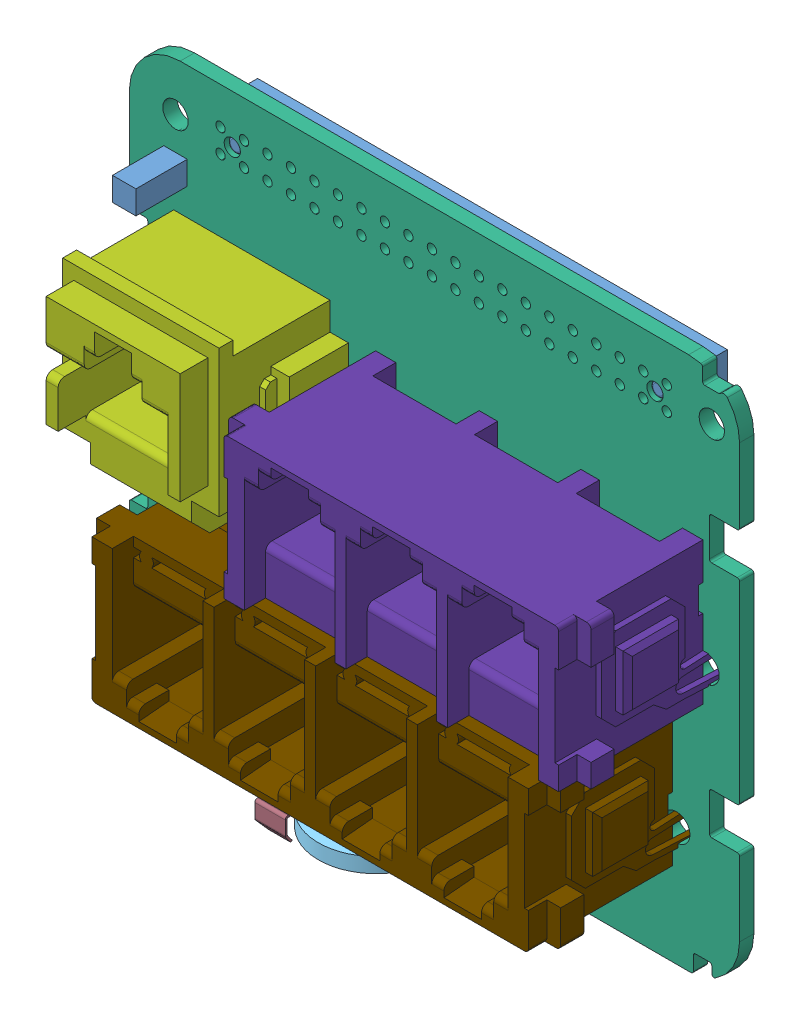
SolidWorks assembly Mainboard_Rpi4, configuration Défaut. Lengths in mm.
Overall size (66 57.75 22.04).
213 component instances, 24 part files, 0 mates.
Components (placement in the parent):
- Mainboard_Rpi4.step-1: Mainboard_Rpi4.step [Défaut] at origin size (66 57.75 22.04)
  - J5.step-1: J5.step [Défaut] at origin size (50.8 7.2 4.95)
    - m20-7812045_asm.step-1: m20-7812045_asm.step [Défaut] at (4.8701 0.0001 -1.7297) x (1 0 0) z (0 1 0) size (50.8 4.95 7.2)
      - M20-78120_MOULD.step-1: M20-78120_MOULD.step [Défaut] at origin size (50.8 4.95 5.08)
      - M20-781_CONTACT.step-1: M20-781_CONTACT.step [Défaut] at (-0.75 1.3 -2.135) size (1.5 2.8 2.83)
      - M20-781_CONTACT.step-2: M20-781_CONTACT.step [Défaut] at (1.79 1.3 -2.135) size (1.5 2.8 2.83)
      - M20-781_CONTACT.step-3: M20-781_CONTACT.step [Défaut] at (4.33 1.3 -2.135) size (1.5 2.8 2.83)
      - M20-781_CONTACT.step-4: M20-781_CONTACT.step [Défaut] at (6.87 1.3 -2.135) size (1.5 2.8 2.83)
      - M20-781_CONTACT.step-5: M20-781_CONTACT.step [Défaut] at (9.41 1.3 -2.135) size (1.5 2.8 2.83)
      - M20-781_CONTACT.step-6: M20-781_CONTACT.step [Défaut] at (11.95 1.3 -2.135) size (1.5 2.8 2.83)
      - M20-781_CONTACT.step-7: M20-781_CONTACT.step [Défaut] at (14.49 1.3 -2.135) size (1.5 2.8 2.83)
      - M20-781_CONTACT.step-8: M20-781_CONTACT.step [Défaut] at (17.03 1.3 -2.135) size (1.5 2.8 2.83)
      - M20-781_CONTACT.step-9: M20-781_CONTACT.step [Défaut] at (19.57 1.3 -2.135) size (1.5 2.8 2.83)
      - M20-781_CONTACT.step-10: M20-781_CONTACT.step [Défaut] at (22.11 1.3 -2.135) size (1.5 2.8 2.83)
      - M20-781_CONTACT.step-11: M20-781_CONTACT.step [Défaut] at (24.65 1.3 -2.135) size (1.5 2.8 2.83)
      - M20-781_CONTACT.step-12: M20-781_CONTACT.step [Défaut] at (27.19 1.3 -2.135) size (1.5 2.8 2.83)
      - M20-781_CONTACT.step-13: M20-781_CONTACT.step [Défaut] at (29.73 1.3 -2.135) size (1.5 2.8 2.83)
      - M20-781_CONTACT.step-14: M20-781_CONTACT.step [Défaut] at (32.27 1.3 -2.135) size (1.5 2.8 2.83)
      - M20-781_CONTACT.step-15: M20-781_CONTACT.step [Défaut] at (34.81 1.3 -2.135) size (1.5 2.8 2.83)
      - M20-781_CONTACT.step-16: M20-781_CONTACT.step [Défaut] at (37.35 1.3 -2.135) size (1.5 2.8 2.83)
      - M20-781_CONTACT.step-17: M20-781_CONTACT.step [Défaut] at (39.89 1.3 -2.135) size (1.5 2.8 2.83)
      - M20-781_CONTACT.step-18: M20-781_CONTACT.step [Défaut] at (42.43 1.3 -2.135) size (1.5 2.8 2.83)
      - M20-781_CONTACT.step-19: M20-781_CONTACT.step [Défaut] at (44.97 1.3 -2.135) size (1.5 2.8 2.83)
      - M20-781_CONTACT.step-20: M20-781_CONTACT.step [Défaut] at (47.51 1.3 -2.135) size (1.5 2.8 2.83)
      - M20-781_CONTACT.step-21: M20-781_CONTACT.step [Défaut] at (0.75 1.3 2.135) x (-1 0 0) z (0 0 -1) size (1.5 2.8 2.83)
      - M20-781_CONTACT.step-22: M20-781_CONTACT.step [Défaut] at (3.29 1.3 2.135) x (-1 0 0) z (0 0 -1) size (1.5 2.8 2.83)
      - M20-781_CONTACT.step-23: M20-781_CONTACT.step [Défaut] at (5.83 1.3 2.135) x (-1 0 0) z (0 0 -1) size (1.5 2.8 2.83)
      - M20-781_CONTACT.step-24: M20-781_CONTACT.step [Défaut] at (8.37 1.3 2.135) x (-1 0 0) z (0 0 -1) size (1.5 2.8 2.83)
      - M20-781_CONTACT.step-25: M20-781_CONTACT.step [Défaut] at (10.91 1.3 2.135) x (-1 0 0) z (0 0 -1) size (1.5 2.8 2.83)
      - M20-781_CONTACT.step-26: M20-781_CONTACT.step [Défaut] at (13.45 1.3 2.135) x (-1 0 0) z (0 0 -1) size (1.5 2.8 2.83)
      - M20-781_CONTACT.step-27: M20-781_CONTACT.step [Défaut] at (15.99 1.3 2.135) x (-1 0 0) z (0 0 -1) size (1.5 2.8 2.83)
      - M20-781_CONTACT.step-28: M20-781_CONTACT.step [Défaut] at (18.53 1.3 2.135) x (-1 0 0) z (0 0 -1) size (1.5 2.8 2.83)
      - M20-781_CONTACT.step-29: M20-781_CONTACT.step [Défaut] at (21.07 1.3 2.135) x (-1 0 0) z (0 0 -1) size (1.5 2.8 2.83)
      - M20-781_CONTACT.step-30: M20-781_CONTACT.step [Défaut] at (23.61 1.3 2.135) x (-1 0 0) z (0 0 -1) size (1.5 2.8 2.83)
      - M20-781_CONTACT.step-31: M20-781_CONTACT.step [Défaut] at (26.15 1.3 2.135) x (-1 0 0) z (0 0 -1) size (1.5 2.8 2.83)
      - M20-781_CONTACT.step-32: M20-781_CONTACT.step [Défaut] at (28.69 1.3 2.135) x (-1 0 0) z (0 0 -1) size (1.5 2.8 2.83)
      - M20-781_CONTACT.step-33: M20-781_CONTACT.step [Défaut] at (31.23 1.3 2.135) x (-1 0 0) z (0 0 -1) size (1.5 2.8 2.83)
      - M20-781_CONTACT.step-34: M20-781_CONTACT.step [Défaut] at (33.77 1.3 2.135) x (-1 0 0) z (0 0 -1) size (1.5 2.8 2.83)
      - M20-781_CONTACT.step-35: M20-781_CONTACT.step [Défaut] at (36.31 1.3 2.135) x (-1 0 0) z (0 0 -1) size (1.5 2.8 2.83)
      - M20-781_CONTACT.step-36: M20-781_CONTACT.step [Défaut] at (38.85 1.3 2.135) x (-1 0 0) z (0 0 -1) size (1.5 2.8 2.83)
      - M20-781_CONTACT.step-37: M20-781_CONTACT.step [Défaut] at (41.39 1.3 2.135) x (-1 0 0) z (0 0 -1) size (1.5 2.8 2.83)
      - M20-781_CONTACT.step-38: M20-781_CONTACT.step [Défaut] at (43.93 1.3 2.135) x (-1 0 0) z (0 0 -1) size (1.5 2.8 2.83)
      - M20-781_CONTACT.step-39: M20-781_CONTACT.step [Défaut] at (46.47 1.3 2.135) x (-1 0 0) z (0 0 -1) size (1.5 2.8 2.83)
      - M20-781_CONTACT.step-40: M20-781_CONTACT.step [Défaut] at (49.01 1.3 2.135) x (-1 0 0) z (0 0 -1) size (1.5 2.8 2.83)
  - C3.step-1: C3.step [Défaut] at origin size (2.2 1.45 1.4)
    - 870407824.step-1: 870407824.step [Défaut] at (-0.508 -11.732 -2.9519) size (2.2 1.45 1.4)
      - Extruded.step-1: Extruded.step [Défaut] at origin size (2.2 1.45 1.4)
  - C2.step-1: C2.step [Défaut] at origin size (2.2 1.45 1.4)
    - 870407824.step-1: 870407824.step [Défaut] at (50.8 -29.718 -2.9519) size (2.2 1.45 1.4)
      - Extruded.step-1: Extruded.step [Défaut] at origin size (2.2 1.45 1.4)
  - U10.step-1: U10.step [Défaut] at origin size (2 2 0.8)
    - 870408096.step-1: 870408096.step [Défaut] at (7.747 -16.873 -2.4519) size (2 2 0.8)
      - Extruded-0.step-1: Extruded-0.step [Défaut] at origin size (2 2 0.8)
  - U9.step-1: U9.step [Défaut] at origin size (2 2 0.8)
    - 870408096.step-1: 870408096.step [Défaut] at (11.049 -16.873 -2.4519) size (2 2 0.8)
      - Extruded-0.step-1: Extruded-0.step [Défaut] at origin size (2 2 0.8)
  - U8.step-1: U8.step [Défaut] at origin size (2 2 0.8)
    - 870408096.step-1: 870408096.step [Défaut] at (4.445 -16.873 -2.4519) size (2 2 0.8)
      - Extruded-0.step-1: Extruded-0.step [Défaut] at origin size (2 2 0.8)
  - R3.step-1: R3.step [Défaut] at origin size (1.4 2.15 0.7)
    - 870408368.step-1: 870408368.step [Défaut] at (8.89 -9.779 -2.2519) size (1.4 2.15 0.7)
      - Extruded-1.step-1: Extruded-1.step [Défaut] at origin size (1.4 2.15 0.7)
  - Q8.step-1: Q8.step [Défaut] at origin size (2.2 1.35 1)
    - 870406736.step-1: 870406736.step [Défaut] at (1.524 -8.938 -2.6519) size (2.2 1.35 1)
      - Extruded-2.step-1: Extruded-2.step [Défaut] at origin size (2.2 1.35 1)
  - J3.step-1: J3.step [Défaut] at origin size (20.9 19.8 19.5)
    - TM3RA-88_RGB13278208.step-1: TM3RA-88_RGB13278208.step [Défaut] at (8.2551 -24.0349 12.5) x (1 0 0) z (0 0 1) size (20.9 19.8 19.5)
  - U7.step-1: U7.step [Défaut] at origin size (2 2 0.8)
    - 870408096.step-1: 870408096.step [Défaut] at (26.369 -39.41 -2.4519) size (2 2 0.8)
      - Extruded-0.step-1: Extruded-0.step [Défaut] at origin size (2 2 0.8)
  - U6.step-1: U6.step [Défaut] at origin size (2 2 0.8)
    - 870408096.step-1: 870408096.step [Défaut] at (49.099 -15.349 -2.4519) size (2 2 0.8)
      - Extruded-0.step-1: Extruded-0.step [Défaut] at origin size (2 2 0.8)
  - U5.step-1: U5.step [Défaut] at origin size (2 2 0.8)
    - 870408096.step-1: 870408096.step [Défaut] at (37.291 -39.41 -2.4519) size (2 2 0.8)
      - Extruded-0.step-1: Extruded-0.step [Défaut] at origin size (2 2 0.8)
  - U4.step-1: U4.step [Défaut] at origin size (2 2 0.8)
    - 870408096.step-1: 870408096.step [Défaut] at (38.05 -15.349 -2.4519) size (2 2 0.8)
      - Extruded-0.step-1: Extruded-0.step [Défaut] at origin size (2 2 0.8)
  - U3.step-1: U3.step [Défaut] at origin size (2 2 0.8)
    - 870408096.step-1: 870408096.step [Défaut] at (15.32 -39.41 -2.4519) size (2 2 0.8)
      - Extruded-0.step-1: Extruded-0.step [Défaut] at origin size (2 2 0.8)
  - U2.step-1: U2.step [Défaut] at origin size (2 2 0.8)
    - 870408096.step-1: 870408096.step [Défaut] at (48.34 -39.41 -2.4519) size (2 2 0.8)
      - Extruded-0.step-1: Extruded-0.step [Défaut] at origin size (2 2 0.8)
  - U1.step-1: U1.step [Défaut] at origin size (2 2 0.8)
    - 870408096.step-1: 870408096.step [Défaut] at (27.128 -15.349 -2.4519) size (2 2 0.8)
      - Extruded-0.step-1: Extruded-0.step [Défaut] at origin size (2 2 0.8)
  - Q7.step-1: Q7.step [Défaut] at origin size (1.35 2.2 1)
    - 870407280.step-1: 870407280.step [Défaut] at (10.24 -39.16 -2.6519) size (1.35 2.2 1)
      - Extruded-3.step-1: Extruded-3.step [Défaut] at origin size (1.35 2.2 1)
  - Q6.step-1: Q6.step [Défaut] at origin size (1.35 2.2 1)
    - 870407280.step-1: 870407280.step [Défaut] at (21.289 -39.16 -2.6519) size (1.35 2.2 1)
      - Extruded-3.step-1: Extruded-3.step [Défaut] at origin size (1.35 2.2 1)
  - Q5.step-1: Q5.step [Défaut] at origin size (1.35 2.2 1)
    - 870407280.step-1: 870407280.step [Défaut] at (32.211 -39.16 -2.6519) size (1.35 2.2 1)
      - Extruded-3.step-1: Extruded-3.step [Défaut] at origin size (1.35 2.2 1)
  - Q4.step-1: Q4.step [Défaut] at origin size (1.35 2.2 1)
    - 870407280.step-1: 870407280.step [Défaut] at (43.26 -39.16 -2.6519) size (1.35 2.2 1)
      - Extruded-3.step-1: Extruded-3.step [Défaut] at origin size (1.35 2.2 1)
  - Q3.step-1: Q3.step [Défaut] at origin size (1.35 2.2 1)
    - 870407280.step-1: 870407280.step [Défaut] at (54.179 -15.599 -2.6519) size (1.35 2.2 1)
      - Extruded-3.step-1: Extruded-3.step [Défaut] at origin size (1.35 2.2 1)
  - Q2.step-1: Q2.step [Défaut] at origin size (1.35 2.2 1)
    - 870407280.step-1: 870407280.step [Défaut] at (43.13 -15.599 -2.6519) size (1.35 2.2 1)
      - Extruded-3.step-1: Extruded-3.step [Défaut] at origin size (1.35 2.2 1)
  - Q1.step-1: Q1.step [Défaut] at origin size (1.35 2.2 1)
    - 870407280.step-1: 870407280.step [Défaut] at (32.208 -15.599 -2.6519) size (1.35 2.2 1)
      - Extruded-3.step-1: Extruded-3.step [Défaut] at origin size (1.35 2.2 1)
  - R2.step-1: R2.step [Défaut] at origin size (2.15 1.4 0.7)
    - 870406464.step-1: 870406464.step [Défaut] at (43.514 -45.974 -2.2519) size (2.15 1.4 0.7)
      - Extruded-4.step-1: Extruded-4.step [Défaut] at origin size (2.15 1.4 0.7)
  - R1.step-1: R1.step [Défaut] at origin size (2.15 1.4 0.7)
    - 870406464.step-1: 870406464.step [Défaut] at (43.514 -48.26 -2.2519) size (2.15 1.4 0.7)
      - Extruded-4.step-1: Extruded-4.step [Défaut] at origin size (2.15 1.4 0.7)
  - U11.step-1: U11.step [Défaut] at origin size (4.91 6.03 1.75)
    - 873278928.step-1: 873278928.step [Défaut] at (0.635 -37.084 -1.5519) x (0 -1 0) z (0 0 -1) size (6.03 4.9 1.75)
      - Body.step-1: Body.step [Défaut] at (-1.95 -2.45 0) size (3.91 4.9 1.65)
        - Open_CASCADE_STEP_translator_6.8_10.2.1.step-1: Open_CASCADE_STEP_translator_6.8_10.2.1.step [Défaut] at origin size (3.91 4.9 1.65)
      - Open_CASCADE_STEP_translator_6.8_10.1.step-1: Open_CASCADE_STEP_translator_6.8_10.1.step [Défaut] at (-1.95 -2.45 0.001) size (0.5 0.5 0.01)
      - Leader.step-1: Leader.step [Défaut] at (-1.95 -1.905 0) x (-1 0 0) z (0 0 1) size (1.06 0.41 0.97)
      - Leader.step-2: Leader.step [Défaut] at (-1.95 -0.635 0) x (-1 0 0) z (0 0 1) size (1.06 0.41 0.97)
      - Leader.step-3: Leader.step [Défaut] at (-1.95 0.635 0) x (-1 0 0) z (0 0 1) size (1.06 0.41 0.97)
      - Leader.step-4: Leader.step [Défaut] at (-1.95 1.905 0) x (-1 0 0) z (0 0 1) size (1.06 0.41 0.97)
      - Leader.step-5: Leader.step [Défaut] at (1.95 -1.905 0) size (1.06 0.41 0.97)
      - Leader.step-6: Leader.step [Défaut] at (1.95 -0.635 0) size (1.06 0.41 0.97)
      - Leader.step-7: Leader.step [Défaut] at (1.95 0.635 0) size (1.06 0.41 0.97)
      - Leader.step-8: Leader.step [Défaut] at (1.95 1.905 0) size (1.06 0.41 0.97)
  - J4.step-1: J4.step [Défaut] at origin size (15.42 4.78 16.81)
    - BS-1225-PC.step-1: BS-1225-PC.step [Défaut] at (29.2101 -47.371 0) x (-1 0 0) z (0 1 0) size (15.42 16.81 4.78)
  - Cx2.step-1: Cx2.step [Défaut] at origin size (1.45 2.2 1.4)
    - 870404832.step-1: 870404832.step [Défaut] at (0.705 -26.66 -2.9519) size (1.45 2.2 1.4)
      - Extruded-5.step-1: Extruded-5.step [Défaut] at origin size (1.45 2.2 1.4)
  - Cx1.step-1: Cx1.step [Défaut] at origin size (1.45 2.2 1.4)
    - 870404832.step-1: 870404832.step [Défaut] at (-1.795 -26.66 -2.9519) size (1.45 2.2 1.4)
      - Extruded-5.step-1: Extruded-5.step [Défaut] at origin size (1.45 2.2 1.4)
  - C1.step-1: C1.step [Défaut] at origin size (2.2 1.45 1.4)
    - 870407824.step-1: 870407824.step [Défaut] at (-0.545 -42.926 -2.9519) size (2.2 1.45 1.4)
      - Extruded.step-1: Extruded.step [Défaut] at origin size (2.2 1.45 1.4)
  - U12.step-1: U12.step [Défaut] at origin size (3.7 2 0.9)
    - 873282384.step-1: 873282384.step [Défaut] at (-0.545 -30.9968 -1.5519) x (-1 0 0) z (0 0 -1) size (3.7 2 0.9)
      - Body-6.step-1: Body-6.step [Défaut] at (-1.65 -0.8 0) size (3.3 1.6 0.9)
      - bigPin.step-1: bigPin.step [Défaut] at (-1.85 -1 -0.0033) size (1.2 2 0.01)
      - bigPin.step-2: bigPin.step [Défaut] at (0.65 -1 -0.0033) size (1.2 2 0.01)
  - J1.step-1: J1.step [Défaut] at origin size (39.2 15.4 22.04)
    - TM2RE-1818(50)_RGB13278208.step-1: TM2RE-1818(50)_RGB13278208.step [Défaut] at (39.3359 -11.3181 16) x (1 0 0) z (0 0 1) size (39.2 15.4 22.04)
      - TM2RE-1818(50).step-1: TM2RE-1818(50).step [Défaut] at (0 -7.7 0) size (39.2 15.4 22.04)
  - J2.step-1: J2.step [Défaut] at origin size (50.2 15.4 22.04)
    - TM2RE-2424_RGB13278208.step-1: TM2RE-2424_RGB13278208.step [Défaut] at (47.0601 -35.774 16) x (-1 0 0) z (0 0 1) size (50.2 15.4 22.04)
  - P2.step-1: P2.step [Défaut] at origin size (2.54 2.54 5.55)
    - 870406192.step-1: 870406192.step [Défaut] at (0 -4.826 0) size (2.54 2.54 5.55)
      - Extruded-7.step-1: Extruded-7.step [Défaut] at origin size (2.54 2.54 5.55)
  - R4.step-1: R4.step [Défaut] at origin size (1.7 0.95 0.55)
    - 870422376.step-1: 870422376.step [Défaut] at (50.8 -27.7876 -2.1019) size (1.7 0.95 0.55)
      - Extruded-8.step-1: Extruded-8.step [Défaut] at origin size (1.7 0.95 0.55)
  - R5.step-1: R5.step [Défaut] at origin size (1.7 0.95 0.55)
    - 870422376.step-1: 870422376.step [Défaut] at (47.498 -27.7876 -2.1019) size (1.7 0.95 0.55)
      - Extruded-8.step-1: Extruded-8.step [Défaut] at origin size (1.7 0.95 0.55)
  - R6.step-1: R6.step [Défaut] at origin size (1.7 0.95 0.55)
    - 870422376.step-1: 870422376.step [Défaut] at (31.115 -12.7 -2.1019) size (1.7 0.95 0.55)
      - Extruded-8.step-1: Extruded-8.step [Défaut] at origin size (1.7 0.95 0.55)
  - R7.step-1: R7.step [Défaut] at origin size (1.7 0.95 0.55)
    - 870422376.step-1: 870422376.step [Défaut] at (26.162 -12.7 -2.1019) size (1.7 0.95 0.55)
      - Extruded-8.step-1: Extruded-8.step [Défaut] at origin size (1.7 0.95 0.55)
  - R8.step-1: R8.step [Défaut] at origin size (1.7 0.95 0.55)
    - 870422376.step-1: 870422376.step [Défaut] at (42.037 -12.7148 -2.1019) size (1.7 0.95 0.55)
      - Extruded-8.step-1: Extruded-8.step [Défaut] at origin size (1.7 0.95 0.55)
  - R9.step-1: R9.step [Défaut] at origin size (1.7 0.95 0.55)
    - 870422376.step-1: 870422376.step [Défaut] at (36.97 -12.7 -2.1019) size (1.7 0.95 0.55)
      - Extruded-8.step-1: Extruded-8.step [Défaut] at origin size (1.7 0.95 0.55)
  - R10.step-1: R10.step [Défaut] at origin size (1.7 0.95 0.55)
    - 870422376.step-1: 870422376.step [Défaut] at (52.844 -12.7148 -2.1019) size (1.7 0.95 0.55)
      - Extruded-8.step-1: Extruded-8.step [Défaut] at origin size (1.7 0.95 0.55)
  - R11.step-1: R11.step [Défaut] at origin size (1.7 0.95 0.55)
    - 870422376.step-1: 870422376.step [Défaut] at (48.073 -12.7 -2.1019) size (1.7 0.95 0.55)
      - Extruded-8.step-1: Extruded-8.step [Défaut] at origin size (1.7 0.95 0.55)
  - R12.step-1: R12.step [Défaut] at origin size (1.7 0.95 0.55)
    - 870422376.step-1: 870422376.step [Défaut] at (43.815 -41.402 -2.1019) size (1.7 0.95 0.55)
      - Extruded-8.step-1: Extruded-8.step [Défaut] at origin size (1.7 0.95 0.55)
  - R13.step-1: R13.step [Défaut] at origin size (1.7 0.95 0.55)
    - 870422376.step-1: 870422376.step [Défaut] at (49.093 -42.585 -2.1019) size (1.7 0.95 0.55)
      - Extruded-8.step-1: Extruded-8.step [Défaut] at origin size (1.7 0.95 0.55)
  - R14.step-1: R14.step [Défaut] at origin size (1.7 0.95 0.55)
    - 870422376.step-1: 870422376.step [Défaut] at (32.766 -41.402 -2.1019) size (1.7 0.95 0.55)
      - Extruded-8.step-1: Extruded-8.step [Défaut] at origin size (1.7 0.95 0.55)
  - R15.step-1: R15.step [Défaut] at origin size (1.7 0.95 0.55)
    - 870422376.step-1: 870422376.step [Défaut] at (38.044 -42.2262 -2.1019) size (1.7 0.95 0.55)
      - Extruded-8.step-1: Extruded-8.step [Défaut] at origin size (1.7 0.95 0.55)
  - R16.step-1: R16.step [Défaut] at origin size (1.7 0.95 0.55)
    - 870422376.step-1: 870422376.step [Défaut] at (21.857 -41.402 -2.1019) size (1.7 0.95 0.55)
      - Extruded-8.step-1: Extruded-8.step [Défaut] at origin size (1.7 0.95 0.55)
  - R17.step-1: R17.step [Défaut] at origin size (1.7 0.95 0.55)
    - 870422376.step-1: 870422376.step [Défaut] at (27.122 -42.2262 -2.1019) size (1.7 0.95 0.55)
      - Extruded-8.step-1: Extruded-8.step [Défaut] at origin size (1.7 0.95 0.55)
  - R18.step-1: R18.step [Défaut] at origin size (1.7 0.95 0.55)
    - 870422376.step-1: 870422376.step [Défaut] at (10.821 -41.402 -2.1019) size (1.7 0.95 0.55)
      - Extruded-8.step-1: Extruded-8.step [Défaut] at origin size (1.7 0.95 0.55)
  - R19.step-1: R19.step [Défaut] at origin size (1.7 0.95 0.55)
    - 870422376.step-1: 870422376.step [Défaut] at (16.073 -42.2262 -2.1019) size (1.7 0.95 0.55)
      - Extruded-8.step-1: Extruded-8.step [Défaut] at origin size (1.7 0.95 0.55)
  - R20.step-1: R20.step [Défaut] at origin size (0.95 1.7 0.55)
    - 870405920.step-1: 870405920.step [Défaut] at (13.2927 -21.987 -2.1019) size (0.95 1.7 0.55)
      - Extruded-9.step-1: Extruded-9.step [Défaut] at origin size (0.95 1.7 0.55)
  - R21.step-1: R21.step [Défaut] at origin size (0.95 1.7 0.55)
    - 870405920.step-1: 870405920.step [Défaut] at (14.986 -21.987 -2.1019) size (0.95 1.7 0.55)
      - Extruded-9.step-1: Extruded-9.step [Défaut] at origin size (0.95 1.7 0.55)
  - U13.step-1: U13.step [Défaut] at origin size (8.49 8.49 1)
    - 870411632.step-1: 870411632.step [Défaut] at (17.055 -9.1329 -2.5519) size (8.49 8.49 1)
      - Extruded-10.step-1: Extruded-10.step [Défaut] at origin size (8.49 8.49 1)
  - Free-Models.step-1: Free-Models.step [Défaut] at origin size (12.5 1.6 12.5)
    - 873281360.step-1: 873281360.step [Défaut] at (29.21 -48.336 7.5) x (-1 0 0) z (0 1 0) size (12.5 12.5 1.6)
      - Cylinder.step-1: Cylinder.step [Défaut] at origin size (12.5 12.5 1.6)
  - Board.step-1: Board.step [Défaut] at (0 0 -1.5519) size (66 57.75 1.55)
